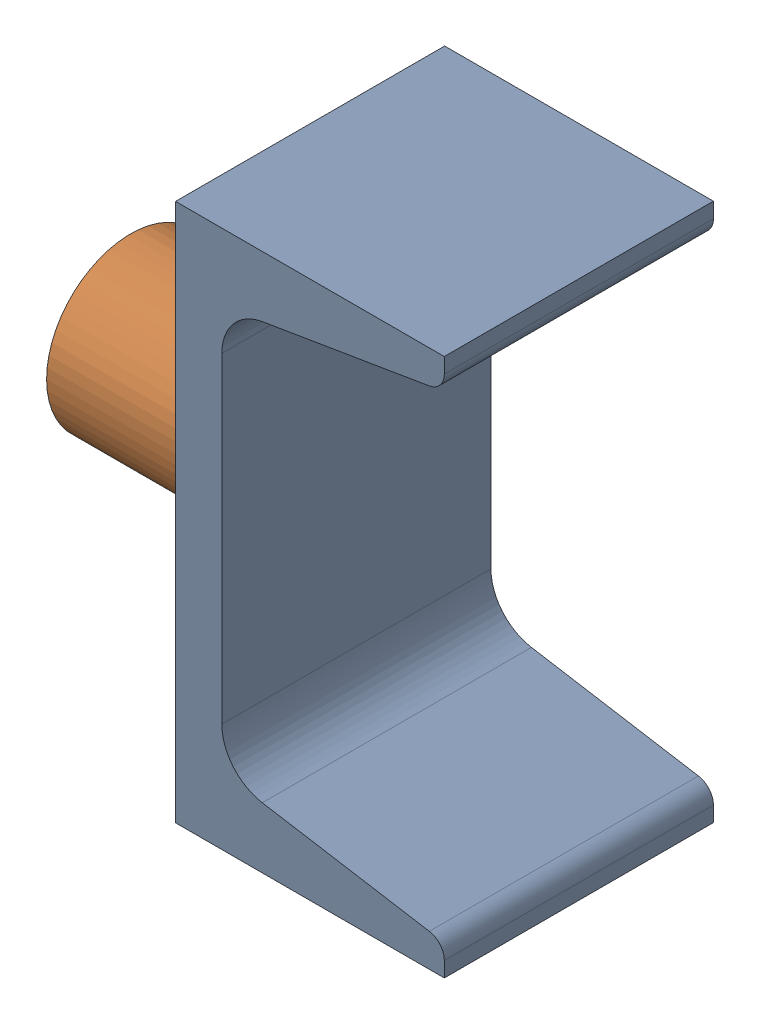
SolidWorks assembly 01-113-00-0-1, configuration Default. Lengths in mm.
Overall size (63.45 76.2 38.1).
2 component instances, 2 part files, 0 mates.
Components (placement in the parent):
- 01-112-00-0-1: 01-112-00-0 [Default] at (-117.0124 -34.5535 49.2974) size (38.05 76.2 38.1)
- 01-111-00-0-1: 01-111-00-0 [Default] at (-142.4124 3.5465 49.2974) x (0 -1 0) z (0 0 1) size (23.81 25.4 23.81)
